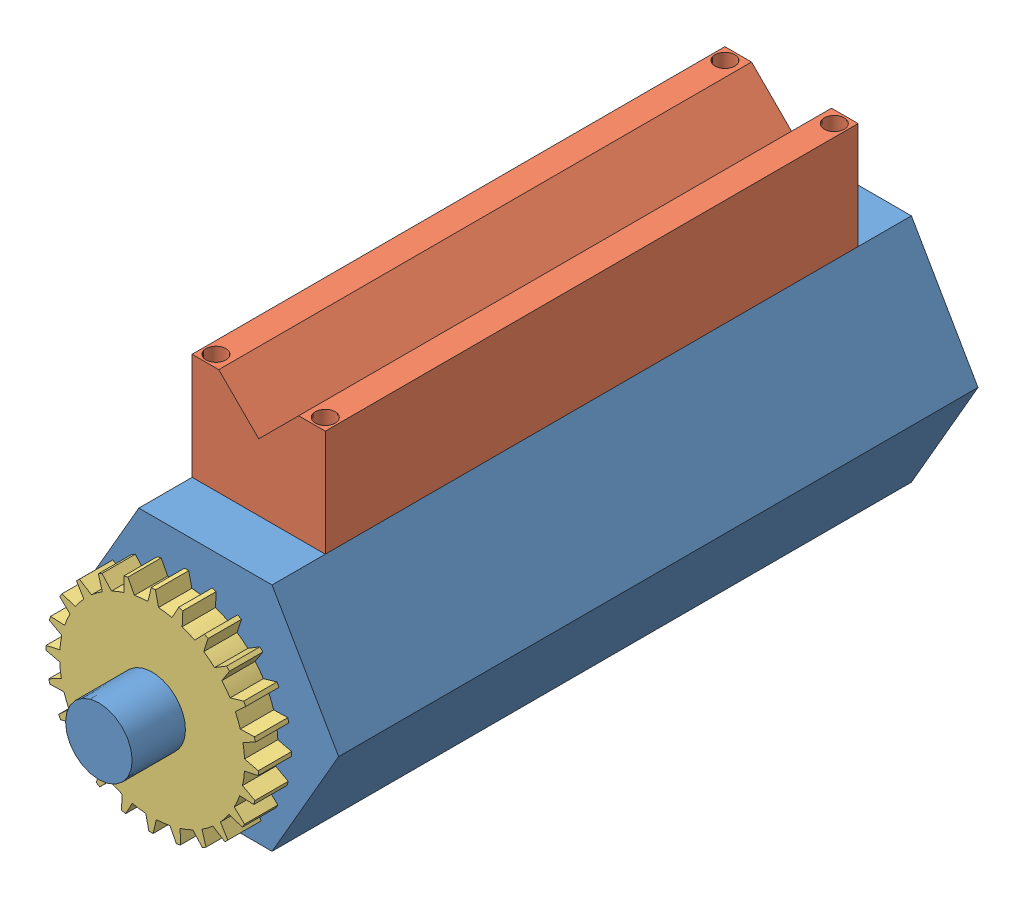
SolidWorks assembly Ensamblaje 10, configuration Predeterminado. Lengths in mm.
Overall size (127 160.79 381).
3 component instances, 3 part files, 5 mates.
Components (placement in the parent):
- exagono 1-1: exagono 1 [Predeterminado] at (-12.2332 0.9939 457.2) size (127 109.99 381)
- base 10-1: base 10 [Predeterminado] at (-43.9832 55.9866 431.8) size (63.5 50.8 254)
- engrane 1-1: engrane 1 [Predeterminado] at (-12.2332 0.9939 466.725) x (0.999934 -0.011529 0) z (0 0 1) size (101.2 101.2 15.88)
Mates (geometry in assembly coordinates):
- Coincidente1: coincident anti-aligned: plane of exagono 1-1 through (19.5168 55.9866 152.4) normal (0 1 0); plane of base 10-1 through (-43.9832 55.9866 177.8) normal (0 -1 0)
- Ancho1: width aligned: plane of exagono 1-1 through (-12.2332 0.9939 457.2) normal (0 0 1); plane of exagono 1-1 through (-12.2332 0.9939 152.4) normal (0 0 -1); plane of base 10-1 through (-43.9832 55.9866 431.8) normal (0 0 1); plane of base 10-1 through (-43.9832 55.9866 177.8) normal (0 0 -1)
- Coincidente2: coincident: line of exagono 1-1 through (-43.9832 55.9866 152.4) axis (0 0 1); plane of base 10-1 through (-43.9832 55.9866 177.8) normal (-1 0 0)
- Concéntrica1: concentric: cylinder of exagono 1-1 through (-12.2332 0.9939 508) axis (0 0 -1) radius 15.875; cylinder of engrane 1-1 through (-12.2332 0.9939 492.4938) axis (0 0 -1) radius 15.875
- Distancia1: distance = 25.4 mm aligned: plane of exagono 1-1 through (-12.2332 0.9939 508) normal (0 0 1); plane of engrane 1-1 through (-12.2332 0.9939 482.6) normal (0 0 1)
